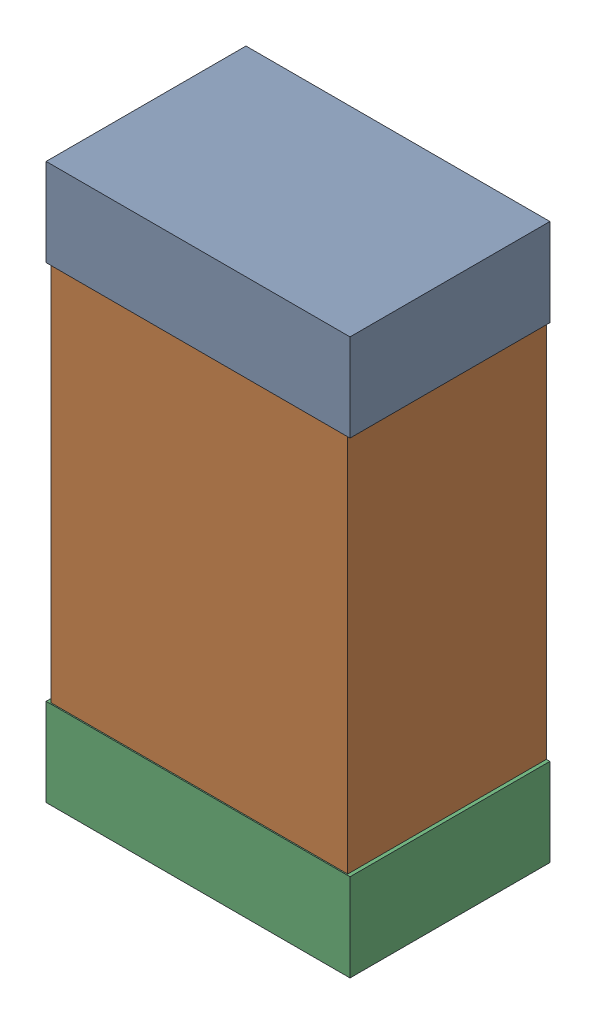
SolidWorks assembly C7Kanaloa_v2.0.0_Power, configuration Default. Lengths in mm.
Overall size (1.3 2.38 0.85).
6 component instances, 2 part files, 0 mates.
Components (placement in the parent):
- 330415056-1: 330415056 [Default] at (66.675 94 0) size (1.3 0.38 0.85)
  - Extruded_2-1: Extruded_2 [Default] at origin size (1.3 0.38 0.85)
- 352877008-1: 352877008 [Default] at (66.675 93 0) size (1.27 2.2 0.85)
  - Extruded_3-1: Extruded_3 [Default] at origin size (1.27 2.2 0.85)
- 330415056-2: 330415056 [Default] at (66.675 92 0) size (1.3 0.38 0.85)
  - Extruded_2-1: Extruded_2 [Default] at origin size (1.3 0.38 0.85)
